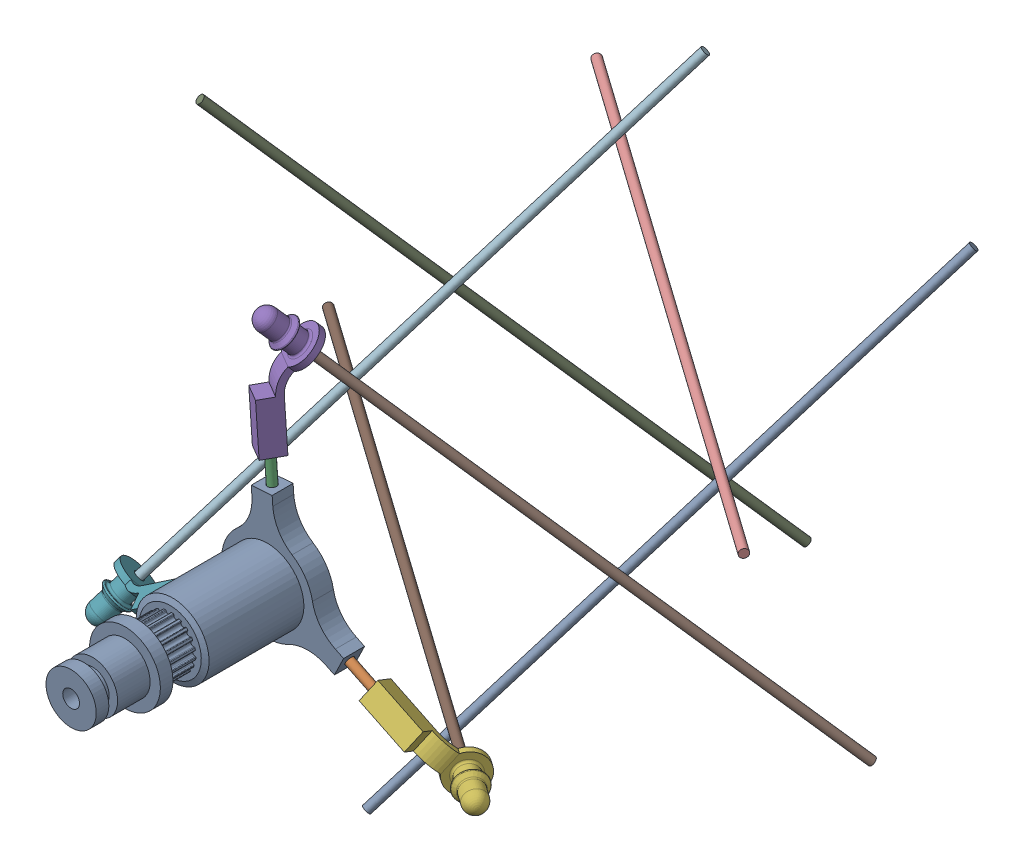
SolidWorks assembly wheel_assembly, configuration longer version. Lengths in mm.
Overall size (212.03 207.89 217).
14 component instances, 4 part files, 13 mates.
Components (placement in the parent):
- wheel_hub-1: wheel_hub [longer version] at (18.845 8.4399 33.0614) x (0.997426 0.071703 0) z (0 0 1) size (35.41 30.67 51.86)
- hub_rods_2mm_dia-1: hub_rods_2mm_dia [Default] at (38.9792 -1.3315 35.5614) x (0.003904 0.008044 0.99996) z (-0.436599 -0.899612 0.008941) size (2 26.76 2)
- hub_rods_2mm_dia-2: hub_rods_2mm_dia [Default] at (17.2403 30.7623 35.5614) x (0.989964 0.071167 0.122092) z (-0.121778 -0.008754 0.992519) size (2 26.76 2)
- hub_rods_2mm_dia-3: hub_rods_2mm_dia [Default] at (0.3156 -4.111 35.5614) x (0.405715 -0.598972 -0.690382) z (0.387173 -0.571598 0.723445) size (2 26.76 2)
- rod_end_cap_hub-1: rod_end_cap_hub [Default] at (18.604 54.3785 30.6161) x (-0.848676 -0.06101 -0.525383) z (0.169536 0.909535 -0.379478) size (9.1 15.63 27.25)
- rod_end_cap_hub-2: rod_end_cap_hub [Default] at (58.7495 -14.3206 30.6161) x (0.371502 0.76548 -0.525383) z (0.702912 -0.60159 -0.379478) size (9.1 15.63 27.25)
- rod_end_cap_hub-3: rod_end_cap_hub [Default] at (-20.8184 -14.7381 30.6161) x (0.477174 -0.70447 -0.525383) z (-0.872448 -0.307945 -0.379478) size (9.1 15.63 27.25)
- simple_icosahedron_wheel-1: simple_icosahedron_wheel [Default] at (45.3812 8.4399 -7.3037) x (-0.816497 0 -0.57735) z (0.408248 0.707107 -0.57735) size (147 147 147)
  - tensegrity_rods_2mm_130mm-1: tensegrity_rods_2mm_130mm [Default] at origin size (2 147 2)
  - tensegrity_rods_2mm_130mm-2: tensegrity_rods_2mm_130mm [Default] at (65 0 0) size (2 147 2)
  - tensegrity_rods_2mm_130mm-5: tensegrity_rods_2mm_130mm [Default] at (32.5 0 32.5) x (0 0 -1) z (0 -1 0) size (2 147 2)
  - tensegrity_rods_2mm_130mm-6: tensegrity_rods_2mm_130mm [Default] at (32.5 0 -32.5) x (0 0 -1) z (0 -1 0) size (2 147 2)
  - tensegrity_rods_2mm_130mm-7: tensegrity_rods_2mm_130mm [Default] at (32.5 32.5 0) x (0 1 0) z (-1 0 0) size (2 147 2)
  - tensegrity_rods_2mm_130mm-8: tensegrity_rods_2mm_130mm [Default] at (32.5 -32.5 0) x (0 1 0) z (-1 0 0) size (2 147 2)
Mates (geometry in assembly coordinates):
- Concentric1: concentric aligned: cone of wheel_hub-1 through (17.4827 27.391 35.5614) axis (0.071703 -0.997426 0); cylinder of hub_rods_2mm_dia-2 through (16.2809 44.1079 35.5614) axis (0.071703 -0.997426 0) radius 1
- Concentric2: concentric anti-aligned: cone of wheel_hub-1 through (35.9383 0.1442 35.5614) axis (-0.899648 0.436616 0); cylinder of hub_rods_2mm_dia-1 through (26.9419 4.5104 35.5614) axis (0.899648 -0.436616 0) radius 1
- Concentric3: concentric anti-aligned: cone of wheel_hub-1 through (3.1141 -2.2155 35.5614) axis (0.827945 0.56081 0); cylinder of hub_rods_2mm_dia-3 through (11.3935 3.3926 35.5614) axis (-0.827945 -0.56081 0) radius 1
- Coincident1: coincident anti-aligned: plane of wheel_hub-1 through (11.3935 3.3926 35.5614) normal (-0.827945 -0.56081 0); plane of hub_rods_2mm_dia-3 through (11.3935 3.3926 35.5614) normal (0.827945 0.56081 0)
- Coincident2: coincident anti-aligned: plane of wheel_hub-1 through (26.9419 4.5104 35.5614) normal (0.899648 -0.436616 0); plane of hub_rods_2mm_dia-1 through (26.9419 4.5104 35.5614) normal (-0.899648 0.436616 0)
- Coincident3: coincident anti-aligned: plane of wheel_hub-1 through (18.1997 17.4168 35.5614) normal (-0.071703 0.997426 0); plane of hub_rods_2mm_dia-2 through (18.1997 17.4168 35.5614) normal (0.071703 -0.997426 0)
- Concentric4: concentric aligned: cylinder of hub_rods_2mm_dia-1 through (26.9419 4.5104 35.5614) axis (0.899648 -0.436616 0) radius 1; cone of rod_end_cap_hub-2 through (42.024 -2.8092 35.5614) axis (0.899648 -0.436616 0)
- Concentric5: concentric anti-aligned: cylinder of hub_rods_2mm_dia-2 through (16.2809 44.1079 35.5614) axis (0.071703 -0.997426 0) radius 1; cone of rod_end_cap_hub-1 through (16.9976 34.1381 35.5614) axis (-0.071703 0.997426 0)
- Concentric6: concentric aligned: cylinder of hub_rods_2mm_dia-3 through (11.3935 3.3926 35.5614) axis (-0.827945 -0.56081 0) radius 1; cone of rod_end_cap_hub-3 through (-2.4865 -6.009 35.5614) axis (-0.827945 -0.56081 0)
- Parallel5: parallel aligned: plane of wheel_hub-1 through (18.845 8.4399 38.0614) normal (0 0 1)
- Concentric17: concentric anti-aligned: cone of rod_end_cap_hub-1 through (15.3449 60.4643 35.174) axis (-0.408248 0.707107 0.57735); cylinder of simple_icosahedron_wheel-1/tensegrity_rods_2mm_130mm-1 through (15.3749 60.4123 35.1316) axis (0.408248 -0.707107 -0.57735) radius 1
- Concentric18: concentric anti-aligned: cone of rod_end_cap_hub-3 through (-24.4593 -20.6034 35.174) axis (-0.408248 -0.707107 0.57735); cylinder of simple_icosahedron_wheel-1/tensegrity_rods_2mm_130mm-7 through (-24.4293 -20.5514 35.1316) axis (0.408248 0.707107 -0.57735) radius 1
- Concentric19: concentric aligned: cone of rod_end_cap_hub-2 through (65.6495 -14.541 35.174) axis (0.816497 0 0.57735); cylinder of simple_icosahedron_wheel-1/tensegrity_rods_2mm_130mm-6 through (-54.4355 -14.541 -49.7389) axis (0.816497 0 0.57735) radius 1
